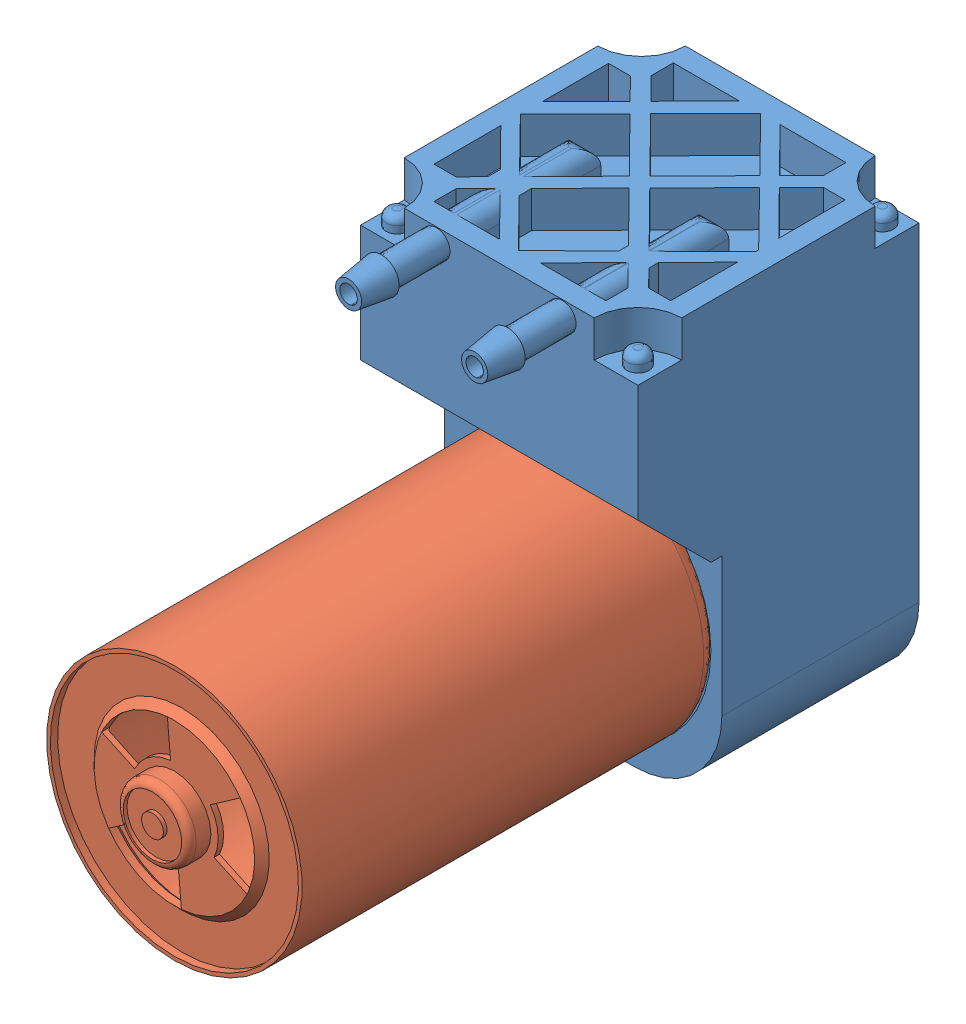
SolidWorks assembly vacuum pump assembly, configuration Default. Lengths in mm.
Overall size (38 62.43 86).
2 component instances, 2 part files, 3 mates.
Components (placement in the parent):
- vacuum section-1: vacuum section [Default] at (48.2505 35.8771 7.1194) size (38 62.43 50.5)
- motor shell-1: motor shell [Default] at (48.2505 23.8771 33.1194) x (0 -1 0) z (0 0 1) size (36.5 36.5 63)
Mates (geometry in assembly coordinates):
- Coincident2: coincident anti-aligned: plane of vacuum section-1 through (48.2505 23.8771 33.1194) normal (0 0 1); plane of motor shell-1 through (48.2505 23.8771 33.1194) normal (0 0 -1)
- Concentric1: concentric aligned: circle of vacuum section-1; circle of motor shell-1
- Parallel1: parallel anti-aligned: plane of motor shell-1 through (48.2505 23.8771 33.1194) normal (0 -1 0)
